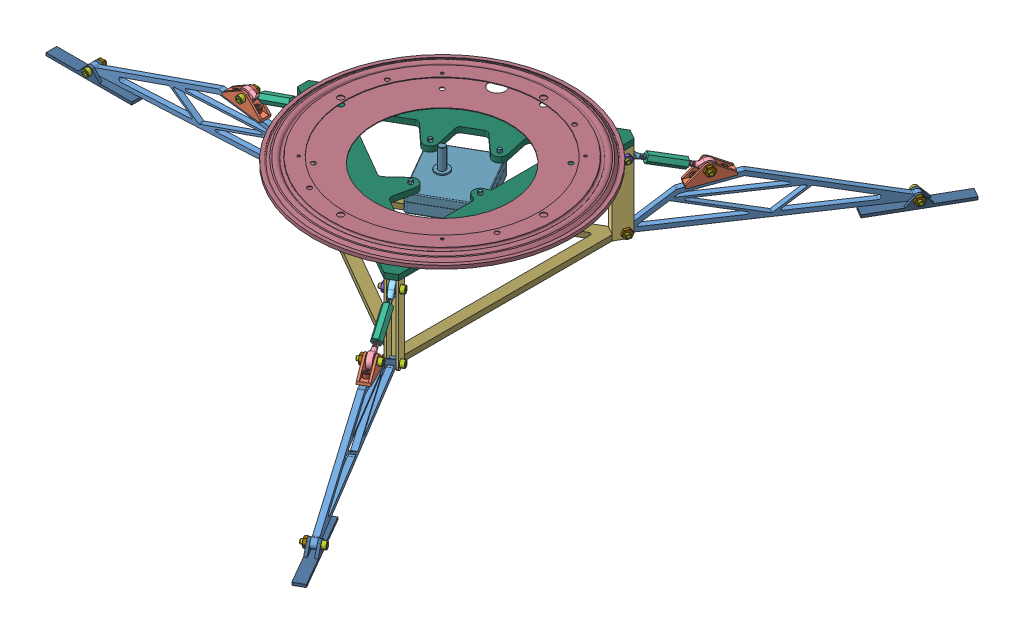
SolidWorks assembly Base Assembly, configuration Default. Lengths in mm.
Overall size (706.14 136.53 814.62).
58 component instances, 15 part files, 0 mates.
Components (placement in the parent):
- Corner Assembly-1: Corner Assembly [Default] at (83.888 69.3381 -9.5412) size (317.5 111.13 23.88)
  - Leg-1: Leg [Default] at (-81.9604 100.7587 355.4692) size (264.16 60.38 6.35)
  - Part2^Corner Assembly-1: Part2^Corner Assembly [Default] at (-188.4761 192.3861 355.4692) x (0.990189 -0.139734 0) z (0.139734 0.990189 0) size (45.57 12.7 19.05)
  - Part3^Corner Assembly-1: Part3^Corner Assembly [Default] at (0 0 358.6442) size (19.05 95.25 12.7)
  - 60645K111_STEEL BALL JOINT ROD END_60645K111-1: 60645K111_STEEL BALL JOINT ROD END_60645K111 [Default] at (112.1046 168.6814 358.6442) x (-0.33035 0.943858 0) z (0 0 1) size (15.88 39.69 15.88)
  - 60645K112_STEEL BALL JOINT ROD END_60645K112-1: 60645K112_STEEL BALL JOINT ROD END_60645K112 [Default] at (160.0526 185.4632 358.6442) x (0.33035 -0.943858 0) z (0 0 1) size (15.88 39.69 15.88)
  - Turnbuckle-1: Turnbuckle [Default] at (154.0591 183.3655 358.6442) x (-0.268128 0.766079 -0.584149) z (-0.943858 -0.33035 0) size (11 9.53 38.1)
  - socket head cap screw_ai_HX-SHCS 0.19-32x0.75x0.75-N-1: socket head cap screw_ai_HX-SHCS 0.19-32x0.75x0.75-N [Default] at (100.1176 164.486 369.8202) x (0 0 -1) z (1 0 0) size (23.88 7.94 7.94)
  - socket head cap screw_ai_HX-SHCS 0.19-32x0.75x0.75-N-2: socket head cap screw_ai_HX-SHCS 0.19-32x0.75x0.75-N [Default] at (172.0396 113.4587 369.8202) x (0 0 -1) z (-0.923728 -0.383049 0) size (23.88 7.94 7.94)
  - socket head cap screw_ai_HX-SHCS 0.19-32x0.75x0.75-N-3: socket head cap screw_ai_HX-SHCS 0.19-32x0.75x0.75-N [Default] at (172.0396 189.6587 369.8202) x (0 0 -1) z (1 0 0) size (23.88 7.94 7.94)
  - machine screw nut hex_ai_MSHXNUT 0.164-36-S-N-1: machine screw nut hex_ai_MSHXNUT 0.164-36-S-N [Default] at (172.0396 189.6587 348.9922) x (0.923728 0.383049 0) z (0 0 -1) size (8.74 10.09 3.3)
  - machine screw nut hex_ai_MSHXNUT 0.190-32-S-N-1: machine screw nut hex_ai_MSHXNUT 0.190-32-S-N [Default] at (100.1176 164.486 348.9922) x (0.923728 0.383049 0) z (0 0 -1) size (9.53 11 3.3)
  - machine screw nut hex_ai_MSHXNUT 0.190-32-S-N-2: machine screw nut hex_ai_MSHXNUT 0.190-32-S-N [Default] at (172.0396 113.4587 348.9922) x (0.923728 0.383049 0) z (0 0 -1) size (9.53 11 3.3)
  - Part5^Corner Assembly-1: Part5^Corner Assembly [Default] at (-81.9604 100.7587 355.4692) x (-1 0 0) z (0 0 -1) size (101.6 14.61 12.7)
  - socket head cap screw_ai_HX-SHCS 0.19-32x0.375x0.375-N-1: socket head cap screw_ai_HX-SHCS 0.19-32x0.375x0.375-N [Default] at (112.0364 158.0585 358.6442) x (-0.139734 -0.990189 0) z (0.939632 -0.1326 0.315449) size (14.35 7.94 7.94)
  - socket head cap screw_ai_HX-SHCS 0.19-32x0.375x0.375-N-2: socket head cap screw_ai_HX-SHCS 0.19-32x0.375x0.375-N [Default] at (86.8856 161.6077 358.6442) x (-0.139734 -0.990189 0) z (0 0 1) size (14.35 7.94 7.94)
  - machine screw nut hex_ai_MSHXNUT 0.190-32-S-N-3: machine screw nut hex_ai_MSHXNUT 0.190-32-S-N [Default] at (-81.9604 100.7587 348.9922) x (0.923728 0.383049 0) z (0 0 -1) size (9.53 11 3.3)
  - socket head cap screw_ai_HX-SHCS 0.19-32x0.75x0.75-N-4: socket head cap screw_ai_HX-SHCS 0.19-32x0.75x0.75-N [Default] at (-81.9604 100.7587 369.8202) x (0 0 -1) z (-0.923728 -0.383049 0) size (23.88 7.94 7.94)
- Corner Assembly-2: Corner Assembly [Default] at (890.4841 69.3381 242.0587) x (-0.5 0 0.866025) z (-0.866025 0 -0.5) size (317.5 111.13 23.88)
  - Leg-1: Leg [Default] at (-81.9604 100.7587 355.4692) size (264.16 60.38 6.35)
  - Part2^Corner Assembly-1: Part2^Corner Assembly [Default] at (-188.4761 192.3861 355.4692) x (0.990189 -0.139734 0) z (0.139734 0.990189 0) size (45.57 12.7 19.05)
  - Part3^Corner Assembly-1: Part3^Corner Assembly [Default] at (0 0 358.6442) size (19.05 95.25 12.7)
  - 60645K111_STEEL BALL JOINT ROD END_60645K111-1: 60645K111_STEEL BALL JOINT ROD END_60645K111 [Default] at (112.1046 168.6814 358.6442) x (-0.33035 0.943858 0) z (0 0 1) size (15.88 39.69 15.88)
  - 60645K112_STEEL BALL JOINT ROD END_60645K112-1: 60645K112_STEEL BALL JOINT ROD END_60645K112 [Default] at (160.0526 185.4632 358.6442) x (0.33035 -0.943858 0) z (0 0 1) size (15.88 39.69 15.88)
  - Turnbuckle-1: Turnbuckle [Default] at (154.0591 183.3655 358.6442) x (-0.268128 0.766079 -0.584149) z (-0.943858 -0.33035 0) size (11 9.53 38.1)
  - socket head cap screw_ai_HX-SHCS 0.19-32x0.75x0.75-N-1: socket head cap screw_ai_HX-SHCS 0.19-32x0.75x0.75-N [Default] at (100.1176 164.486 369.8202) x (0 0 -1) z (1 0 0) size (23.88 7.94 7.94)
  - socket head cap screw_ai_HX-SHCS 0.19-32x0.75x0.75-N-2: socket head cap screw_ai_HX-SHCS 0.19-32x0.75x0.75-N [Default] at (172.0396 113.4587 369.8202) x (0 0 -1) z (-0.923728 -0.383049 0) size (23.88 7.94 7.94)
  - socket head cap screw_ai_HX-SHCS 0.19-32x0.75x0.75-N-3: socket head cap screw_ai_HX-SHCS 0.19-32x0.75x0.75-N [Default] at (172.0396 189.6587 369.8202) x (0 0 -1) z (1 0 0) size (23.88 7.94 7.94)
  - machine screw nut hex_ai_MSHXNUT 0.164-36-S-N-1: machine screw nut hex_ai_MSHXNUT 0.164-36-S-N [Default] at (172.0396 189.6587 348.9922) x (0.923728 0.383049 0) z (0 0 -1) size (8.74 10.09 3.3)
  - machine screw nut hex_ai_MSHXNUT 0.190-32-S-N-1: machine screw nut hex_ai_MSHXNUT 0.190-32-S-N [Default] at (100.1176 164.486 348.9922) x (0.923728 0.383049 0) z (0 0 -1) size (9.53 11 3.3)
  - machine screw nut hex_ai_MSHXNUT 0.190-32-S-N-2: machine screw nut hex_ai_MSHXNUT 0.190-32-S-N [Default] at (172.0396 113.4587 348.9922) x (0.923728 0.383049 0) z (0 0 -1) size (9.53 11 3.3)
  - Part5^Corner Assembly-1: Part5^Corner Assembly [Default] at (-81.9604 100.7587 355.4692) x (-1 0 0) z (0 0 -1) size (101.6 14.61 12.7)
  - socket head cap screw_ai_HX-SHCS 0.19-32x0.375x0.375-N-1: socket head cap screw_ai_HX-SHCS 0.19-32x0.375x0.375-N [Default] at (112.0364 158.0585 358.6442) x (-0.139734 -0.990189 0) z (0.939632 -0.1326 0.315449) size (14.35 7.94 7.94)
  - socket head cap screw_ai_HX-SHCS 0.19-32x0.375x0.375-N-2: socket head cap screw_ai_HX-SHCS 0.19-32x0.375x0.375-N [Default] at (86.8856 161.6077 358.6442) x (-0.139734 -0.990189 0) z (0 0 1) size (14.35 7.94 7.94)
  - machine screw nut hex_ai_MSHXNUT 0.190-32-S-N-3: machine screw nut hex_ai_MSHXNUT 0.190-32-S-N [Default] at (-81.9604 100.7587 348.9922) x (0.923728 0.383049 0) z (0 0 -1) size (9.53 11 3.3)
  - socket head cap screw_ai_HX-SHCS 0.19-32x0.75x0.75-N-4: socket head cap screw_ai_HX-SHCS 0.19-32x0.75x0.75-N [Default] at (-81.9604 100.7587 369.8202) x (0 0 -1) z (-0.923728 -0.383049 0) size (23.88 7.94 7.94)
- Corner Assembly-3: Corner Assembly [Default] at (269.2942 69.3381 814.7914) x (-0.5 0 -0.866025) z (0.866025 0 -0.5) size (317.5 111.13 23.88)
  - Leg-1: Leg [Default] at (-81.9604 100.7587 355.4692) size (264.16 60.38 6.35)
  - Part2^Corner Assembly-1: Part2^Corner Assembly [Default] at (-188.4761 192.3861 355.4692) x (0.990189 -0.139734 0) z (0.139734 0.990189 0) size (45.57 12.7 19.05)
  - Part3^Corner Assembly-1: Part3^Corner Assembly [Default] at (0 0 358.6442) size (19.05 95.25 12.7)
  - 60645K111_STEEL BALL JOINT ROD END_60645K111-1: 60645K111_STEEL BALL JOINT ROD END_60645K111 [Default] at (112.1046 168.6814 358.6442) x (-0.33035 0.943858 0) z (0 0 1) size (15.88 39.69 15.88)
  - 60645K112_STEEL BALL JOINT ROD END_60645K112-1: 60645K112_STEEL BALL JOINT ROD END_60645K112 [Default] at (160.0526 185.4632 358.6442) x (0.33035 -0.943858 0) z (0 0 1) size (15.88 39.69 15.88)
  - Turnbuckle-1: Turnbuckle [Default] at (154.0591 183.3655 358.6442) x (-0.268128 0.766079 -0.584149) z (-0.943858 -0.33035 0) size (11 9.53 38.1)
  - socket head cap screw_ai_HX-SHCS 0.19-32x0.75x0.75-N-1: socket head cap screw_ai_HX-SHCS 0.19-32x0.75x0.75-N [Default] at (100.1176 164.486 369.8202) x (0 0 -1) z (1 0 0) size (23.88 7.94 7.94)
  - socket head cap screw_ai_HX-SHCS 0.19-32x0.75x0.75-N-2: socket head cap screw_ai_HX-SHCS 0.19-32x0.75x0.75-N [Default] at (172.0396 113.4587 369.8202) x (0 0 -1) z (-0.923728 -0.383049 0) size (23.88 7.94 7.94)
  - socket head cap screw_ai_HX-SHCS 0.19-32x0.75x0.75-N-3: socket head cap screw_ai_HX-SHCS 0.19-32x0.75x0.75-N [Default] at (172.0396 189.6587 369.8202) x (0 0 -1) z (1 0 0) size (23.88 7.94 7.94)
  - machine screw nut hex_ai_MSHXNUT 0.164-36-S-N-1: machine screw nut hex_ai_MSHXNUT 0.164-36-S-N [Default] at (172.0396 189.6587 348.9922) x (0.923728 0.383049 0) z (0 0 -1) size (8.74 10.09 3.3)
  - machine screw nut hex_ai_MSHXNUT 0.190-32-S-N-1: machine screw nut hex_ai_MSHXNUT 0.190-32-S-N [Default] at (100.1176 164.486 348.9922) x (0.923728 0.383049 0) z (0 0 -1) size (9.53 11 3.3)
  - machine screw nut hex_ai_MSHXNUT 0.190-32-S-N-2: machine screw nut hex_ai_MSHXNUT 0.190-32-S-N [Default] at (172.0396 113.4587 348.9922) x (0.923728 0.383049 0) z (0 0 -1) size (9.53 11 3.3)
  - Part5^Corner Assembly-1: Part5^Corner Assembly [Default] at (-81.9604 100.7587 355.4692) x (-1 0 0) z (0 0 -1) size (101.6 14.61 12.7)
  - socket head cap screw_ai_HX-SHCS 0.19-32x0.375x0.375-N-1: socket head cap screw_ai_HX-SHCS 0.19-32x0.375x0.375-N [Default] at (112.0364 158.0585 358.6442) x (-0.139734 -0.990189 0) z (0.939632 -0.1326 0.315449) size (14.35 7.94 7.94)
  - socket head cap screw_ai_HX-SHCS 0.19-32x0.375x0.375-N-2: socket head cap screw_ai_HX-SHCS 0.19-32x0.375x0.375-N [Default] at (86.8856 161.6077 358.6442) x (-0.139734 -0.990189 0) z (0 0 1) size (14.35 7.94 7.94)
  - machine screw nut hex_ai_MSHXNUT 0.190-32-S-N-3: machine screw nut hex_ai_MSHXNUT 0.190-32-S-N [Default] at (-81.9604 100.7587 348.9922) x (0.923728 0.383049 0) z (0 0 -1) size (9.53 11 3.3)
  - socket head cap screw_ai_HX-SHCS 0.19-32x0.75x0.75-N-4: socket head cap screw_ai_HX-SHCS 0.19-32x0.75x0.75-N [Default] at (-81.9604 100.7587 369.8202) x (0 0 -1) z (-0.923728 -0.383049 0) size (23.88 7.94 7.94)
- Part8^Base Assembly-1: Part8^Base Assembly [Default] at (83.888 176.4468 349.103) x (-1 0 0) z (0 -1 0) size (224.39 259.1 6.35)
- 6031K190_CORROSION-RESISTANT TURNTABLE-1: 6031K190_CORROSION-RESISTANT TURNTABLE [Default] at (414.5554 282.0219 349.103) size (306.4 8.43 306.4)
- 6409K160_COMPACT SQUARE-FACE DC GEARMOTOR_6409K16-1: 6409K160_COMPACT SQUARE-FACE DC GEARMOTOR_6409K16 [Default] at (425.6731 271.6968 344.7373) x (0.866025 0 -0.5) z (0 -1 0) size (69.85 76.2 93.43)
- Part1^Base Assembly-1: Part1^Base Assembly [Default] at (83.888 271.6968 349.103) x (1 0 0) z (0 1 0) size (252.97 292.1 6.35)
